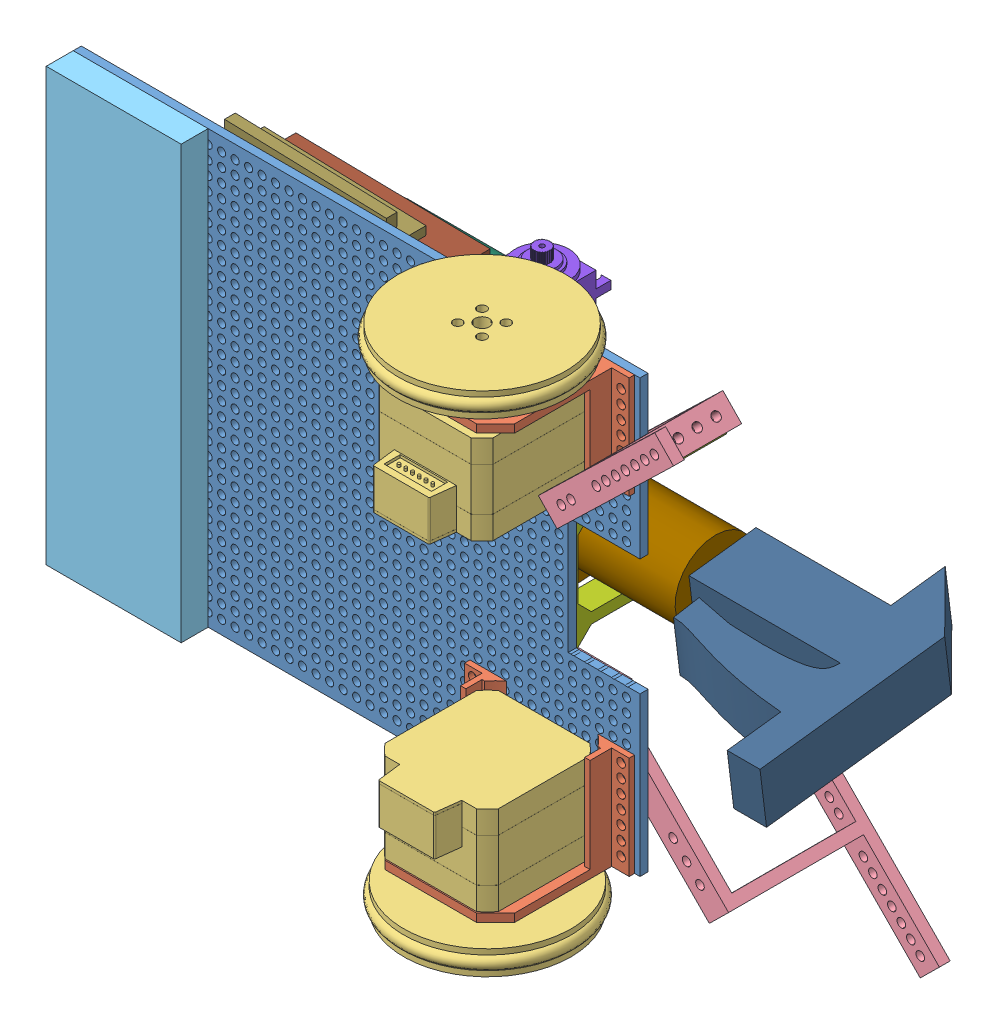
SolidWorks assembly roomba, configuration ﾃﾞﾌｫﾙﾄ. Lengths in mm.
Overall size (279.93 227.23 136.62).
17 component instances, 12 part files, 33 mates.
Components (placement in the parent):
- rumba universal plate-1: rumba universal plate [ﾃﾞﾌｫﾙﾄ] at (-98.343 132.2754 -57.0482) size (210 160 3)
- rumba_moter_wheel-1: rumba_moter_wheel [ﾃﾞﾌｫﾙﾄ] at (-86.0066 78.072 -92.5501) x (0 -1 0) z (0 0 1) size (51.5 65 65)
  - mount.stp-1: mount.stp [ﾃﾞﾌｫﾙﾄ] at (8.4385 13.2505 38.5019) size (38 61 45)
  - stepper (1).stp-1: stepper (1).stp [ﾃﾞﾌｫﾙﾄ] at (16.9385 14.2505 42.5313) size (51 65 65)
- mount.stp-1: mount.stp [ﾃﾞﾌｫﾙﾄ] at (-90.7561 217.6335 -54.0482) x (0 1 0) z (0 0 1) size (38 61 45)
- stepper (1).stp-4: stepper (1).stp [ﾃﾞﾌｫﾙﾄ] at (-91.7561 226.1335 -50.0188) x (0 1 0) z (0 0 1) size (51 65 65)
- photoreflecter_mount×２(床上5mm訂正）-1: photoreflecter_mount×２(床上5mm訂正） [ﾃﾞﾌｫﾙﾄ] at (-69.561 222.6819 -57.0482) x (-0.999844 0.017685 0) z (0 0 -1) size (88.26 88.31 54)
- photoreflecter_mount×２(床上5mm訂正）-2: photoreflecter_mount×２(床上5mm訂正） [ﾃﾞﾌｫﾙﾄ] at (-70.4438 64.7151 -61.0482) x (-0.999988 0.004957 0) z (0 0 1) size (88.26 88.31 54)
- sponge-1: sponge [ﾃﾞﾌｫﾙﾄ] at (-215.3102 155.9046 -54.0482) x (0 -1 0) z (0 0 1) size (160 50 10)
- spray_undermount(cup)-1: spray_undermount(cup) [ﾃﾞﾌｫﾙﾄ] at (-159.2561 137.8381 -100.3198) x (0 -1 0) z (-1 0 0) size (100 76.09 44)
- spray_fasten_-2: spray_fasten_ [ﾃﾞﾌｫﾙﾄ] at (-86.7967 123.6335 -84.0685) x (0 0 -1) z (0 1 0) size (59 10 40)
- spray_fasten_-3: spray_fasten_ [ﾃﾞﾌｫﾙﾄ] at (-81.7155 163.6335 -84.0685) x (0 0 -1) z (0 -1 0) size (59 10 40)
- ceveau moteur MG996R-1: ceveau moteur MG996R [Défaut] at (-109.0399 169.7538 -57.0482) x (0 0 -1) z (1 0 0) size (51.5 44.6 20)
- spray_tank-1: spray_tank [ﾃﾞﾌｫﾙﾄ] at (-49.2561 139.4626 -68.6654) x (0 0.941921 0.335835) z (-1 0 0) size (50 50 150)
- spray_appper-1: spray_appper [ﾃﾞﾌｫﾙﾄ] at (6.7614 151.1038 -72.1889) x (0 0.121869 -0.992546) z (0 -0.992546 -0.121869) size (89.23 69.93 20)
- Lipo_dammy-1: Lipo_dammy [ﾃﾞﾌｫﾙﾄ] at (-184.6342 244.7701 -80.0482) x (0.017452 0.999848 0) z (0 0 1) size (32 72 20)
- Lipo_mount×1つ-1: Lipo_mount×1つ [ﾃﾞﾌｫﾙﾄ] at (-163.8464 178.0813 -72.0482) x (-0.030406 -0.999538 0) z (0 0 1) size (44 60 15)
Mates (geometry in assembly coordinates):
- 一致1: coincident anti-aligned: plane of rumba universal plate-1 through (-259.2561 223.6335 -54.0482) normal (0 1 0); plane of rumba_wheel-2 through (-85.1267 223.6335 -65.7663) normal (0 -1 0)
- 一致2: coincident anti-aligned: plane of rumba universal plate-1 through (-259.2561 63.6335 -54.0482) normal (0 -1 0); plane of rumba_wheel-1 through (-76.9257 63.6335 -63.6817) normal (0 1 0)
- 一致3: coincident anti-aligned: plane of rumba universal plate-1 through (-98.343 132.2754 -57.0482) normal (0 0 -1); plane of rumba _servomoter-1 through (-144.6476 187.643 -57.0482) normal (0 0 1)
- 一致5: coincident anti-aligned: plane of mount.stp-1 through (-81.7561 220.6335 -33.0482) normal (0 -1 0); plane of stepper (1).stp-4 through (-82.7561 220.6335 -40.0188) normal (0 1 0)
- 一致6: coincident anti-aligned: plane of mount.stp-1 through (-102.7561 220.6335 -50.0188) normal (0 0 1); plane of stepper (1).stp-4 through (-65.7855 186.1335 -50.0188) normal (0 0 -1)
- 一致7: coincident anti-aligned: plane of mount.stp-1 through (-103.7561 201.1335 -33.0482) normal (1 0 0); plane of stepper (1).stp-4 through (-103.7561 186.1335 -45.9893) normal (-1 0 0)
- 一致8: coincident aligned: plane of rumba universal plate-1 through (-259.2561 63.6335 -54.0482) normal (0 -1 0); plane of rumba_moter_wheel-1/mount.stp-1 through (-57.2561 63.6335 -54.0482) normal (0 -1 0)
- 一致9: coincident aligned: plane of rumba universal plate-1 through (-259.2561 223.6335 -54.0482) normal (0 1 0); plane of mount.stp-1 through (-106.2561 223.6335 -54.0482) normal (0 1 0)
- 一致11: coincident anti-aligned: plane of rumba universal plate-1 through (-98.343 132.2754 -54.0482) normal (0 0 1); plane of mount.stp-1 through (-64.2561 144.1629 -54.0482) normal (0 0 -1)
- 一致14: coincident anti-aligned: plane of rumba universal plate-1 through (-98.343 132.2754 -54.0482) normal (0 0 1); plane of rumba_moter_wheel-1/mount.stp-1 through (-99.2561 143.104 -54.0482) normal (0 0 -1)
- 同心円1: concentric aligned: circle of rumba universal plate-1; circle of rumba_moter_wheel-1/mount.stp-1
- 同心円2: concentric anti-aligned: circle of rumba universal plate-1; circle of mount.stp-1
- 一致15: coincident anti-aligned: plane of photoreflecter_mount×２(床上5mm訂正）-2 through (-70.4438 64.7151 -57.0482) normal (0 0 1); plane of rumba universal plate-1 through (-98.343 132.2754 -57.0482) normal (0 0 -1)
- 同心円3: concentric aligned: cylinder of rumba universal plate-1; cylinder of photoreflecter_mount×２(床上5mm訂正）-2 through (-64.2561 103.6335 -61.0482) axis (0 0 1) radius 1.6
- 一致18: coincident anti-aligned: plane of rumba universal plate-1 through (-98.343 132.2754 -57.0482) normal (0 0 -1); plane of photoreflecter_mount×２(床上5mm訂正）-1 through (-69.561 222.6819 -57.0482) normal (0 0 1)
- 同心円6: concentric anti-aligned: circle of rumba universal plate-1; cylinder of photoreflecter_mount×２(床上5mm訂正）-1 through (-64.2561 183.6335 -57.0482) axis (0 0 -1) radius 1.6
- 一致19: coincident anti-aligned: plane of rumba universal plate-1 through (-98.343 132.2754 -54.0482) normal (0 0 1); plane of sponge-1 through (-215.3102 155.9046 -54.0482) normal (0 0 -1)
- 一致20: coincident aligned: plane of rumba universal plate-1 through (-259.2561 223.6335 -54.0482) normal (-1 0 0); plane of sponge-1 through (-259.2561 223.6335 -44.0482) normal (-1 0 0)
- 一致21: coincident aligned: plane of rumba universal plate-1 through (-259.2561 223.6335 -54.0482) normal (0 1 0); plane of sponge-1 through (-209.2561 223.6335 -44.0482) normal (0 1 0)
- 一致22: coincident anti-aligned: plane of rumba universal plate-1 through (-98.343 132.2754 -57.0482) normal (0 0 -1); plane of spray_undermount(cup)-1 through (-203.2561 193.6335 -57.0482) normal (0 0 1)
- 一致23: coincident anti-aligned: plane of rumba universal plate-1 through (-98.343 132.2754 -57.0482) normal (0 0 -1); plane of spray_fasten_-2 through (-86.7967 123.6335 -57.0482) normal (0 0 1)
- 一致24: coincident anti-aligned: plane of rumba universal plate-1 through (-98.343 132.2754 -57.0482) normal (0 0 -1); plane of spray_fasten_-3 through (-81.7155 163.6335 -57.0482) normal (0 0 1)
- 一致25: coincident anti-aligned: plane of spray_fasten_-2 through (-89.2561 143.6335 -57.0482) normal (0 1 0); plane of spray_fasten_-3 through (-79.2561 143.6335 -57.0482) normal (0 -1 0)
- 一致26: coincident aligned: plane of spray_fasten_-2 through (-79.2561 127.6335 -61.0482) normal (1 0 0); plane of spray_fasten_-3 through (-79.2561 159.6335 -61.0482) normal (1 0 0)
- 同心円8: concentric anti-aligned: cylinder of rumba universal plate-1 through (-84.2561 178.6335 -57.0482) axis (0 0 1) radius 1.5; cylinder of spray_fasten_-3 through (-84.2561 178.6335 -57.0482) axis (0 0 -1) radius 1.6
- 同心円9: concentric aligned: circle of rumba universal plate-1; cylinder of spray_undermount(cup)-1 through (-164.2561 98.6335 -67.0482) axis (0 0 1) radius 1.6
- 同心円10: concentric aligned: circle of rumba universal plate-1; cylinder of spray_undermount(cup)-1 through (-164.2561 188.6335 -67.0482) axis (0 0 1) radius 1.6
- 一致27: coincident anti-aligned: plane of rumba universal plate-1 through (-98.343 132.2754 -57.0482) normal (0 0 -1); plane of ceveau moteur MG996R-1 through (-109.0399 206.5538 -57.0482) normal (0 0 1)
- 一致29: coincident anti-aligned: plane of spray_undermount(cup)-1 through (-199.2561 143.6335 -96.1343) normal (1 0 0); plane of spray_tank-1 through (-199.2561 144.2342 -82.0482) normal (-1 0 0)
- 正接1: tangent anti-aligned: plane of rumba universal plate-1 through (-98.343 132.2754 -57.0482) normal (0 0 -1); cylinder of spray_tank-1 through (-199.2561 144.2342 -82.0482) axis (1 0 0) radius 25
- 一致30: coincident anti-aligned: plane of spray_tank-1 through (-49.2561 144.2342 -82.0482) normal (1 0 0); plane of spray_appper-1 through (-49.2561 131.2529 -74.6263) normal (-1 0 0)
- 一致31: coincident anti-aligned: plane of spray_undermount(cup)-1 through (-203.2561 193.6335 -60.0482) normal (0 0 -1); plane of Lipo_dammy-1 through (-184.6342 244.7701 -60.0482) normal (0 0 1)
- 一致35: coincident anti-aligned: plane of rumba universal plate-1 through (-98.343 132.2754 -57.0482) normal (0 0 -1); plane of Lipo_mount×1つ-1 through (-163.8464 178.0813 -57.0482) normal (0 0 1)
